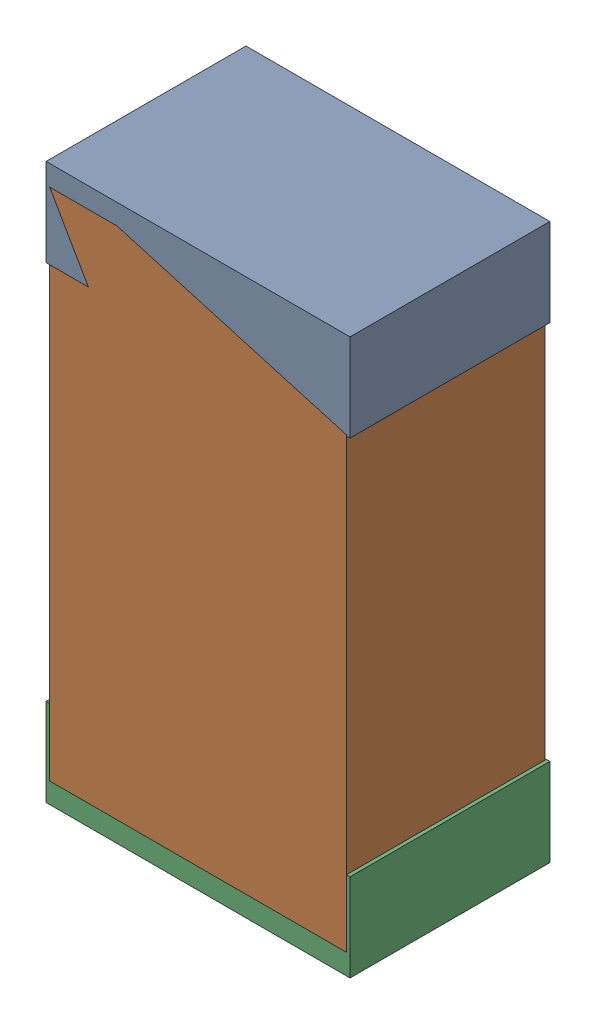
SolidWorks assembly R3, configuration Default. Lengths in mm.
Overall size (1.3 2.38 0.85).
6 component instances, 2 part files, 0 mates.
Components (placement in the parent):
- 402662288-1: 402662288 [Default] at (102.616 68.31 -1.9574) size (1.3 0.38 0.85)
  - Extruded_16-1: Extruded_16 [Default] at origin size (1.3 0.38 0.85)
- 402662416-1: 402662416 [Default] at (102.616 67.31 -1.9524) size (1.27 2.2 0.85)
  - Extruded_17-1: Extruded_17 [Default] at origin size (1.27 2.2 0.85)
- 402662288-2: 402662288 [Default] at (102.616 66.31 -1.9574) size (1.3 0.38 0.85)
  - Extruded_16-1: Extruded_16 [Default] at origin size (1.3 0.38 0.85)
